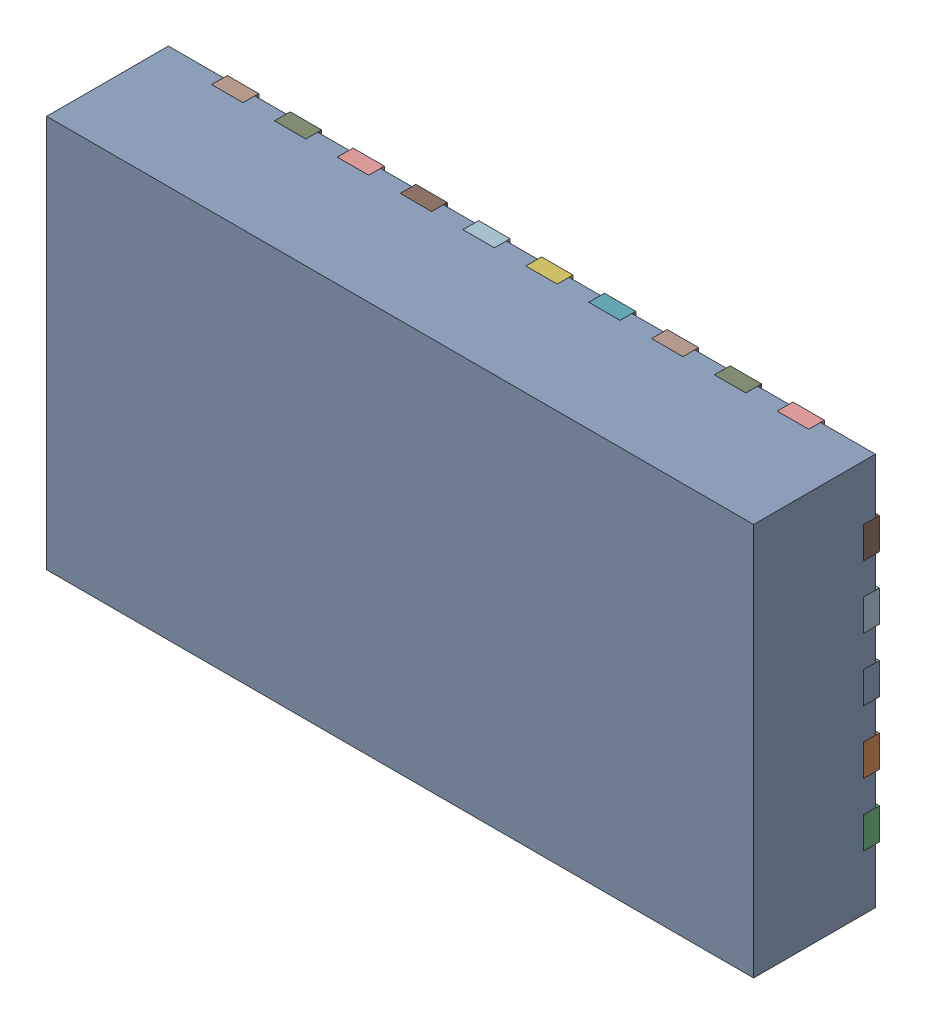
SolidWorks assembly U11, configuration Défaut. Lengths in mm.
Overall size (4.5 2.5 0.8).
36 component instances, 33 part files, 0 mates.
Components (placement in the parent):
- RNH0030A-1: RNH0030A [Défaut] at (49.7016 -26.2692 0) x (0 -1 0) z (0 0 1) size (2.5 4.5 0.8)
  - BODY-QFN-1: BODY-QFN [Défaut] at (0 0 0.025) x (1 0 0) z (0 -1 0) size (2.5 0.78 4.5)
  - FRAME-RNH0030A-1: FRAME-RNH0030A [Défaut] x (1 0 0) z (0 -1 0) size (2.5 0.2 4.5)
    - Open CASCADE STEP translator 7.5 2.204.1.2.1-1: Open CASCADE STEP translator 7.5 2.204.1.2.1 [Défaut] at origin size (1.4 0.2 3.4)
    - Open CASCADE STEP translator 7.5 2.204.1.2.2-1: Open CASCADE STEP translator 7.5 2.204.1.2.2 [Défaut] at origin size (0.3 0.1 0.2)
    - Open CASCADE STEP translator 7.5 2.204.1.2.3-1: Open CASCADE STEP translator 7.5 2.204.1.2.3 [Défaut] at origin size (0.3 0.1 0.2)
    - Open CASCADE STEP translator 7.5 2.204.1.2.4-1: Open CASCADE STEP translator 7.5 2.204.1.2.4 [Défaut] at origin size (0.3 0.1 0.2)
    - Open CASCADE STEP translator 7.5 2.204.1.2.5-1: Open CASCADE STEP translator 7.5 2.204.1.2.5 [Défaut] at origin size (0.3 0.1 0.2)
    - Open CASCADE STEP translator 7.5 2.204.1.2.6-1: Open CASCADE STEP translator 7.5 2.204.1.2.6 [Défaut] at origin size (0.3 0.1 0.2)
    - Open CASCADE STEP translator 7.5 2.204.1.2.7-1: Open CASCADE STEP translator 7.5 2.204.1.2.7 [Défaut] at origin size (0.3 0.1 0.2)
    - Open CASCADE STEP translator 7.5 2.204.1.2.8-1: Open CASCADE STEP translator 7.5 2.204.1.2.8 [Défaut] at origin size (0.3 0.1 0.2)
    - Open CASCADE STEP translator 7.5 2.204.1.2.9-1: Open CASCADE STEP translator 7.5 2.204.1.2.9 [Défaut] at origin size (0.3 0.1 0.2)
    - Open CASCADE STEP translator 7.5 2.204.1.2.10-1: Open CASCADE STEP translator 7.5 2.204.1.2.10 [Défaut] at origin size (0.3 0.1 0.2)
    - Open CASCADE STEP translator 7.5 2.204.1.2.11-1: Open CASCADE STEP translator 7.5 2.204.1.2.11 [Défaut] at origin size (0.3 0.1 0.2)
    - Open CASCADE STEP translator 7.5 2.204.1.2.12-1: Open CASCADE STEP translator 7.5 2.204.1.2.12 [Défaut] at origin size (0.3 0.1 0.2)
    - Open CASCADE STEP translator 7.5 2.204.1.2.13-1: Open CASCADE STEP translator 7.5 2.204.1.2.13 [Défaut] at origin size (0.3 0.1 0.2)
    - Open CASCADE STEP translator 7.5 2.204.1.2.14-1: Open CASCADE STEP translator 7.5 2.204.1.2.14 [Défaut] at origin size (0.3 0.1 0.2)
    - Open CASCADE STEP translator 7.5 2.204.1.2.15-1: Open CASCADE STEP translator 7.5 2.204.1.2.15 [Défaut] at origin size (0.3 0.1 0.2)
    - Open CASCADE STEP translator 7.5 2.204.1.2.16-1: Open CASCADE STEP translator 7.5 2.204.1.2.16 [Défaut] at origin size (0.3 0.1 0.2)
    - Open CASCADE STEP translator 7.5 2.204.1.2.17-1: Open CASCADE STEP translator 7.5 2.204.1.2.17 [Défaut] at origin size (0.3 0.1 0.2)
    - Open CASCADE STEP translator 7.5 2.204.1.2.18-1: Open CASCADE STEP translator 7.5 2.204.1.2.18 [Défaut] at origin size (0.3 0.1 0.2)
    - Open CASCADE STEP translator 7.5 2.204.1.2.19-1: Open CASCADE STEP translator 7.5 2.204.1.2.19 [Défaut] at origin size (0.3 0.1 0.2)
    - Open CASCADE STEP translator 7.5 2.204.1.2.20-1: Open CASCADE STEP translator 7.5 2.204.1.2.20 [Défaut] at origin size (0.3 0.1 0.2)
    - Open CASCADE STEP translator 7.5 2.204.1.2.21-1: Open CASCADE STEP translator 7.5 2.204.1.2.21 [Défaut] at origin size (0.3 0.1 0.2)
    - Open CASCADE STEP translator 7.5 2.204.1.2.22-1: Open CASCADE STEP translator 7.5 2.204.1.2.22 [Défaut] at origin size (0.2 0.1 0.3)
    - Open CASCADE STEP translator 7.5 2.204.1.2.23-1: Open CASCADE STEP translator 7.5 2.204.1.2.23 [Défaut] at origin size (0.2 0.1 0.3)
    - Open CASCADE STEP translator 7.5 2.204.1.2.24-1: Open CASCADE STEP translator 7.5 2.204.1.2.24 [Défaut] at origin size (0.2 0.1 0.3)
    - Open CASCADE STEP translator 7.5 2.204.1.2.25-1: Open CASCADE STEP translator 7.5 2.204.1.2.25 [Défaut] at origin size (0.2 0.1 0.3)
    - Open CASCADE STEP translator 7.5 2.204.1.2.26-1: Open CASCADE STEP translator 7.5 2.204.1.2.26 [Défaut] at origin size (0.2 0.1 0.3)
    - Open CASCADE STEP translator 7.5 2.204.1.2.27-1: Open CASCADE STEP translator 7.5 2.204.1.2.27 [Défaut] at origin size (0.2 0.1 0.3)
    - Open CASCADE STEP translator 7.5 2.204.1.2.28-1: Open CASCADE STEP translator 7.5 2.204.1.2.28 [Défaut] at origin size (0.2 0.1 0.3)
    - Open CASCADE STEP translator 7.5 2.204.1.2.29-1: Open CASCADE STEP translator 7.5 2.204.1.2.29 [Défaut] at origin size (0.2 0.1 0.3)
    - Open CASCADE STEP translator 7.5 2.204.1.2.30-1: Open CASCADE STEP translator 7.5 2.204.1.2.30 [Défaut] at origin size (0.2 0.1 0.3)
    - Open CASCADE STEP translator 7.5 2.204.1.2.31-1: Open CASCADE STEP translator 7.5 2.204.1.2.31 [Défaut] at origin size (0.2 0.1 0.3)
- 8260085744-1: 8260085744 [Défaut] at (49.8286 -26.3962 0) size (0.25 0.25 0.25)
  - Extruded_982-1: Extruded_982 [Défaut] at origin size (0.25 0.25 0.25)
